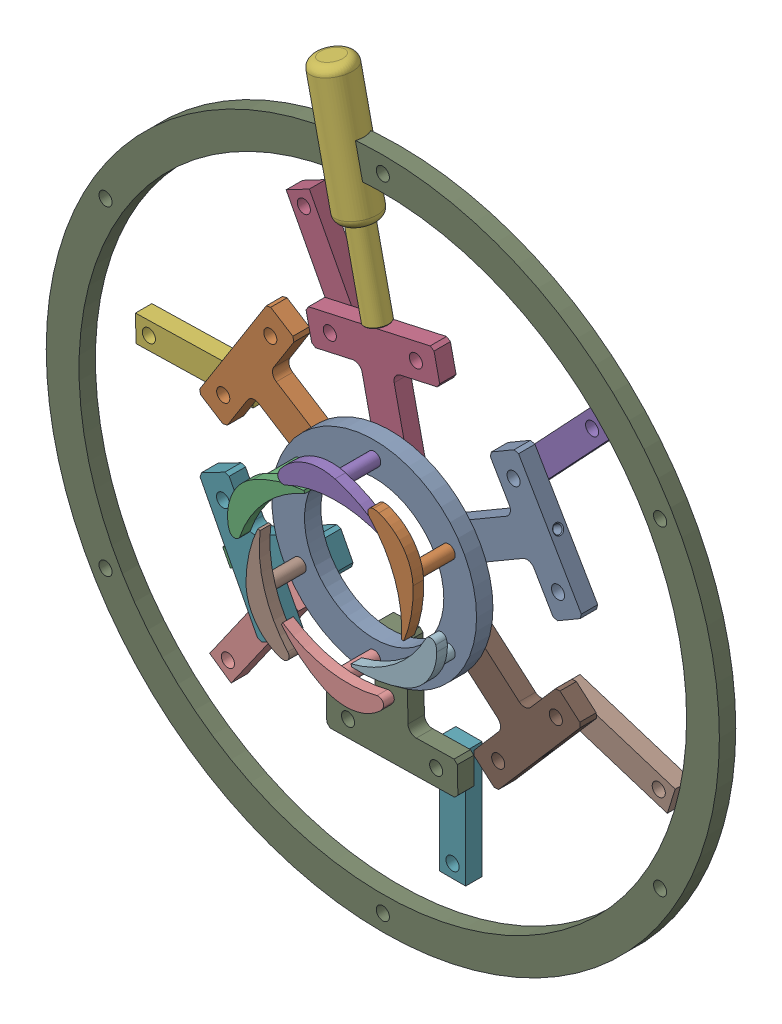
SolidWorks assembly GV000 no links, configuration Default. Lengths in mm.
Overall size (410.8 447.28 61.3).
28 component instances, 7 part files, 17 mates.
Components (placement in the parent):
- GV006-1: GV006 [Default] at origin size (125 125 10)
- GV Sub Assembly-1: GV Sub Assembly [Default] at (-45.4663 26.25 -10) x (0.534102 0.84542 0) z (0 0 1) size (80 78.32 47.3)
  - GV001-1: GV001 [Default] at origin size (80 70 10)
  - GV005-1: GV005 [Default] at (0 0 35.8) size (62.16 25.89 47.3)
- GV Sub Assembly-2: GV Sub Assembly [Default] at (0 52.5 -10) x (0.976457 0.215711 0) z (0 0 1) size (80 78.32 47.3)
  - GV001-1: GV001 [Default] at origin size (80 70 10)
  - GV005-1: GV005 [Default] at (0 0 35.8) size (62.16 25.89 47.3)
- GV002-1: GV002 [Default] at (-23.7282 159.9103 -10) x (-0.215711 0.976457 0) z (0.532389 0.117611 -0.83829) size (142 24 24)
- GV Sub Assembly-3: GV Sub Assembly [Default] at (-45.4663 -26.25 -10) x (-0.460825 0.887491 0) z (0 0 1) size (80 78.32 47.3)
  - GV001-1: GV001 [Default] at origin size (80 70 10)
  - GV005-1: GV005 [Default] at (0 0 35.8) size (62.16 25.89 47.3)
- GV Sub Assembly-4: GV Sub Assembly [Default] at (0 -52.5 -10) x (-0.999823 -0.018827 0) z (0 0 1) size (80 78.32 47.3)
  - GV001-1: GV001 [Default] at origin size (80 70 10)
  - GV005-1: GV005 [Default] at (0 0 35.8) size (62.16 25.89 47.3)
- GV Sub Assembly-5: GV Sub Assembly [Default] at (45.4663 -26.25 -10) x (-0.654153 -0.756362 0) z (0 0 1) size (80 78.32 47.3)
  - GV001-1: GV001 [Default] at origin size (80 70 10)
  - GV005-1: GV005 [Default] at (0 0 35.8) size (62.16 25.89 47.3)
- GV Sub Assembly-8: GV Sub Assembly [Default] at (45.4663 26.25 -10) x (0.50408 -0.863657 0) z (0 0 1) size (80 78.32 47.3)
  - GV001-1: GV001 [Default] at origin size (80 70 10)
  - GV005-1: GV005 [Default] at (0 0 35.8) size (62.16 25.89 47.3)
- GV004-1: GV004 [Default] at (-98.7158 -53.8995 -10) x (-0.460825 0.887491 0) z (-0.887491 -0.460825 0) size (10 24 20.8)
- GV003-10: GV003 [Default] at (-49.9722 120.0226 -20) x (0.88456 0.466426 0) z (0 0 1) size (16 71.4 10)
- GV003-11: GV003 [Default] at (94.0581 94.8725 -20) x (0.728741 -0.684789 0) z (0 0 1) size (16 71.4 10)
- GV003-12: GV003 [Default] at (-129.7973 29.5734 -20) x (0.023103 -0.999733 0) z (0 0 1) size (16 71.4 10)
- GV003-13: GV003 [Default] at (27.8366 -129.6847 -20) size (16 71.4 10)
- GV003-14: GV003 [Default] at (127.2836 -46.9901 -20) x (0.302475 0.953157 0) z (0 0 1) size (16 71.4 10)
- gigaring-1: gigaring [Default] at (-5.3885 -0.2713 -10.6709) size (410.8 410.8 10)
- GV003-15: GV003 [Default] at (-93.3475 -95.8449 -20) x (0.818779 -0.574109 0) z (0 0 1) size (16 71.4 10)
Mates (geometry in assembly coordinates):
- Hinge1: hinge anti-aligned: cylinder of GV Sub Assembly-2/GV001-1 through (0 52.5 -15) axis (0 0 1) radius 4; circle of GV006-1; plane of GV Sub Assembly-2/GV001-1 through (0 52.5 -5) normal (0 0 1); plane of GV006-1 through (0 0 -5) normal (0 0 -1)
- Hinge2: hinge anti-aligned: circle of GV Sub Assembly-1/GV001-1; circle of GV006-1; plane of GV Sub Assembly-1/GV001-1 through (-45.4663 26.25 -5) normal (0 0 1); plane of GV006-1 through (0 0 -5) normal (0 0 -1)
- Concentric1: concentric aligned: line of GV Sub Assembly-2/GV001-1 through (-12.9426 111.0874 -10) axis (-0.215711 0.976457 0); line of GV002-1 through (-10.462 99.8582 -10) axis (-0.215711 0.976457 0)
- Hinge7: hinge anti-aligned: cylinder of GV Sub Assembly-3/GV001-1 through (-45.4663 -26.25 -15) axis (0 0 1) radius 4; cylinder of GV006-1 through (-45.4663 -26.25 -5) axis (0 0 1) radius 4; plane of GV Sub Assembly-3/GV001-1 through (-45.4663 -26.25 -5) normal (0 0 1); plane of GV006-1 through (0 0 -5) normal (0 0 -1)
- Hinge13: hinge anti-aligned: cylinder of GV Sub Assembly-4/GV001-1 through (0 -52.5 -15) axis (0 0 1) radius 4; cylinder of GV006-1 through (0 -52.5 -5) axis (0 0 1) radius 4; plane of GV Sub Assembly-4/GV001-1 through (0 -52.5 -5) normal (0 0 1); plane of GV006-1 through (0 0 -5) normal (0 0 -1)
- Hinge17: hinge anti-aligned: cylinder of GV Sub Assembly-5/GV001-1 through (45.4663 -26.25 -15) axis (0 0 1) radius 4; cylinder of GV006-1 through (45.4663 -26.25 -5) axis (0 0 1) radius 4; plane of GV Sub Assembly-5/GV001-1 through (45.4663 -26.25 -5) normal (0 0 1); plane of GV006-1 through (0 0 -5) normal (0 0 -1)
- Hinge20: hinge anti-aligned: cylinder of GV Sub Assembly-8/GV001-1 through (45.4663 26.25 -15) axis (0 0 1) radius 4; cylinder of GV006-1 through (45.4663 26.25 -5) axis (0 0 1) radius 4; plane of GV Sub Assembly-8/GV001-1 through (45.4663 26.25 -5) normal (0 0 1); plane of GV006-1 through (0 0 -5) normal (0 0 -1)
- Coincident1: coincident anti-aligned: plane of GV Sub Assembly-2/GV001-1 through (-52.0009 102.459 -5) normal (-0.215711 0.976457 0); plane of GV002-1 through (-12.9426 111.0874 -10) normal (0.215711 -0.976457 0)
- Concentric2: concentric aligned: cylinder of GV Sub Assembly-3/GV001-1 through (-98.7158 -53.8995 -10) axis (-0.887491 -0.460825 0) radius 2.5; cylinder of GV004-1 through (-97.2958 -53.1622 -10) axis (-0.887491 -0.460825 0) radius 3.5
- Coincident4: coincident anti-aligned: plane of GV Sub Assembly-3/GV001-1 through (-80.2828 -89.3991 -5) normal (-0.887491 -0.460825 0); plane of GV004-1 through (-98.7158 -53.8995 -10) normal (0.887491 0.460825 0)
- Coincident5: coincident anti-aligned: plane of GV Sub Assembly-3/GV001-1 through (-45.4663 -26.25 -15) normal (0 0 -1); plane of GV004-1 through (-99.5999 -48.7247 -15) normal (0 0 1)
- Hinge28: hinge anti-aligned: cylinder of GV003-12 through (-102.1047 30.2133 -25) axis (0 0 1) radius 4; cylinder of GV003-12 through (-102.1047 30.2133 -15) axis (0 0 1) radius 4; plane of GV Sub Assembly-1/GV001-1 through (-129.7973 29.5734 -15) normal (0 0 1); plane of GV Sub Assembly-1/GV001-1 through (-45.4663 26.25 -15) normal (0 0 -1)
- Hinge29: hinge anti-aligned: cylinder of GV003-10 through (-37.0522 95.5203 -25) axis (0 0 1) radius 4; cylinder of GV Sub Assembly-2/GV001-1 through (-37.0522 95.5203 -15) axis (0 0 1) radius 4; plane of GV Sub Assembly-2/GV001-1 through (0 52.5 -15) normal (0 0 -1); plane of GV003-10 through (-49.9722 120.0226 -15) normal (0 0 1)
- Hinge30: hinge anti-aligned: cylinder of GV003-11 through (75.0894 74.6864 -25) axis (0 0 1) radius 4; cylinder of GV Sub Assembly-8/GV001-1 through (75.0894 74.6864 -15) axis (0 0 1) radius 4; plane of GV Sub Assembly-8/GV001-1 through (45.4663 26.25 -15) normal (0 0 -1); plane of GV003-11 through (94.0581 94.8725 -15) normal (0 0 1)
- Hinge31: hinge anti-aligned: cylinder of GV003-14 through (100.8812 -38.6115 -25) axis (0 0 1) radius 4; cylinder of GV003-14 through (100.8812 -38.6115 -15) axis (0 0 1) radius 4; plane of GV Sub Assembly-5/GV001-1 through (127.2836 -46.9901 -15) normal (0 0 1); plane of GV Sub Assembly-5/GV001-1 through (45.4663 -26.25 -15) normal (0 0 -1)
- Hinge32: hinge anti-aligned: cylinder of GV003-13 through (27.8366 -101.9847 -25) axis (0 0 1) radius 4; cylinder of GV003-13 through (27.8366 -101.9847 -15) axis (0 0 1) radius 4; plane of GV Sub Assembly-4/GV001-1 through (27.8366 -129.6847 -15) normal (0 0 1); plane of GV Sub Assembly-4/GV001-1 through (0 -52.5 -15) normal (0 0 -1)
- Hinge33: hinge anti-aligned: cylinder of GV003-15 through (-77.4447 -73.1648 -25) axis (0 0 1) radius 4; cylinder of GV003-15 through (-77.4447 -73.1648 -15) axis (0 0 1) radius 4; plane of GV Sub Assembly-3/GV001-1 through (-93.3475 -95.8449 -15) normal (0 0 1); plane of GV Sub Assembly-3/GV001-1 through (-45.4663 -26.25 -15) normal (0 0 -1)
